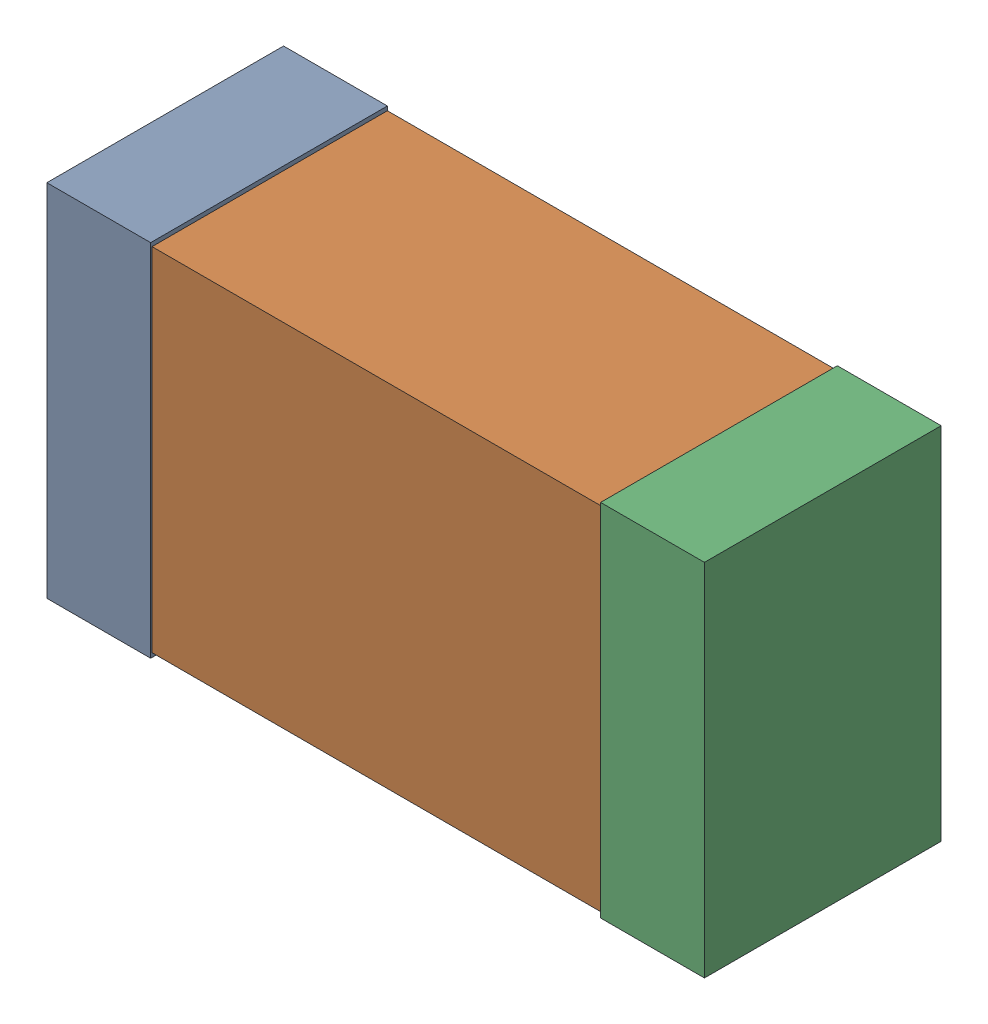
SolidWorks assembly C1Kanaloa_v2.0.0_Power, configuration Default. Lengths in mm.
Overall size (2.38 1.3 0.85).
6 component instances, 2 part files, 0 mates.
Components (placement in the parent):
- 352877648-1: 352877648 [Default] at (82.225 119.7 0) size (0.38 1.3 0.85)
  - Extruded_14-1: Extruded_14 [Default] at origin size (0.38 1.3 0.85)
- 352877904-1: 352877904 [Default] at (83.225 119.7 0) size (2.2 1.27 0.85)
  - Extruded_18-1: Extruded_18 [Default] at origin size (2.2 1.27 0.85)
- 352877648-2: 352877648 [Default] at (84.225 119.7 0) size (0.38 1.3 0.85)
  - Extruded_14-1: Extruded_14 [Default] at origin size (0.38 1.3 0.85)
